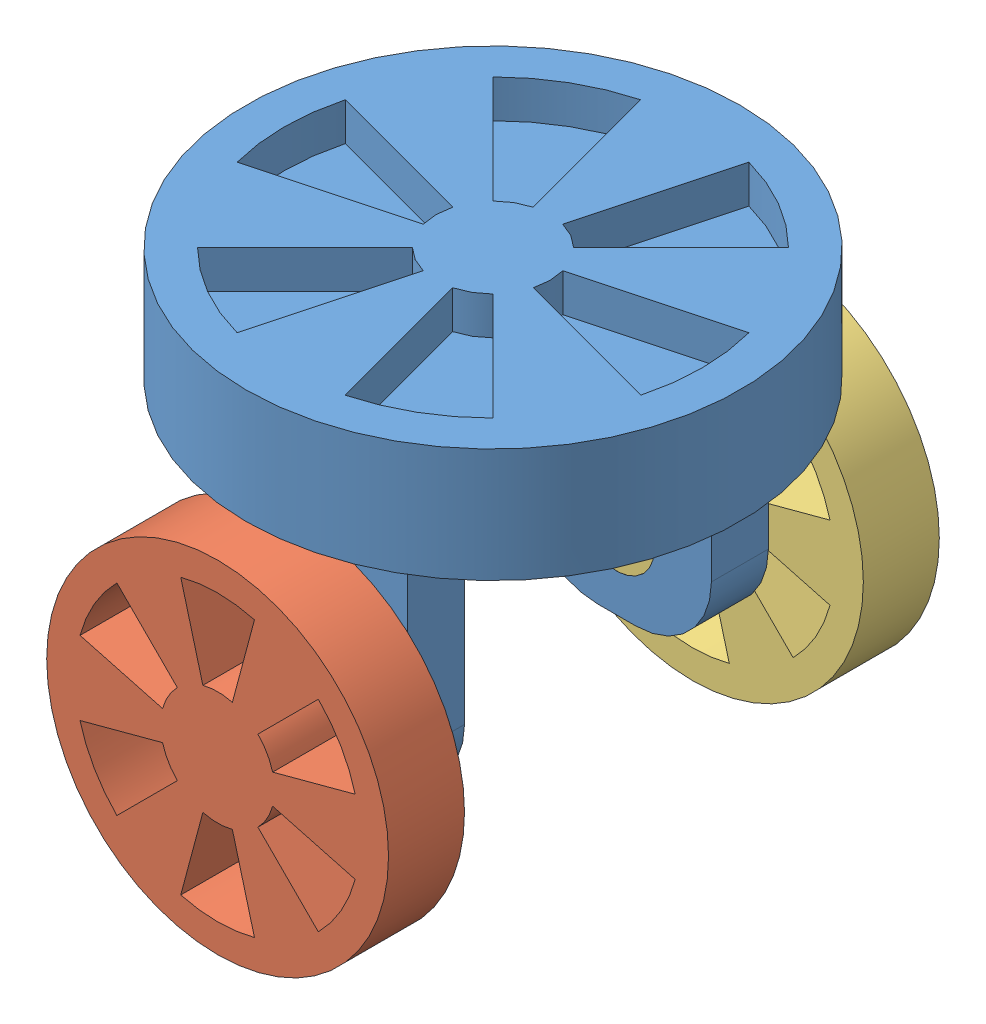
SolidWorks assembly 装配体8, configuration 默认. Lengths in mm.
Overall size (130 125 145).
3 component instances, 3 part files, 4 mates.
Components (placement in the parent):
- turntable_2-1: turntable_2 [默认] at (-0.6664 14.5256 130) size (130 100 130)
- wheel_2_1-1: wheel_2_1 [默认] at (-0.6664 -35.4744 162.5) x (0 0 1) z (-1 0 0) size (40 90 90)
- wheel_2_2-1: wheel_2_2 [默认] at (-0.6664 -35.4744 97.5) x (0 0 -1) z (1 0 0) size (40 90 90)
Mates (geometry in assembly coordinates):
- 同心1: concentric: cylinder of turntable_2-1 through (-0.6664 -35.4744 65) axis (0 0 1) radius 10; cylinder of ? through (-0.6664 -35.4744 193.5379) axis (0 0 -1) radius 10
- 重合1: coincident: plane of assembly; plane of assembly; plane of turntable_2-1 through (-25.6664 -55.4744 162.5) normal (0 0 -1); plane of wheel_2_1-1 through (-0.6664 -35.4744 162.5) normal (0 0 -1)
- 同心2: concentric: cylinder of turntable_2-1 through (-0.6664 -35.4744 65) axis (0 0 1) radius 10; cylinder of ? through (-0.6664 -35.4744 62.3455) axis (0 0 1) radius 10
- 重合2: coincident: plane of assembly; plane of assembly; plane of turntable_2-1 through (-25.6664 -55.4744 97.5) normal (0 0 1); plane of wheel_2_2-1 through (-0.6664 -35.4744 97.5) normal (0 0 1)
